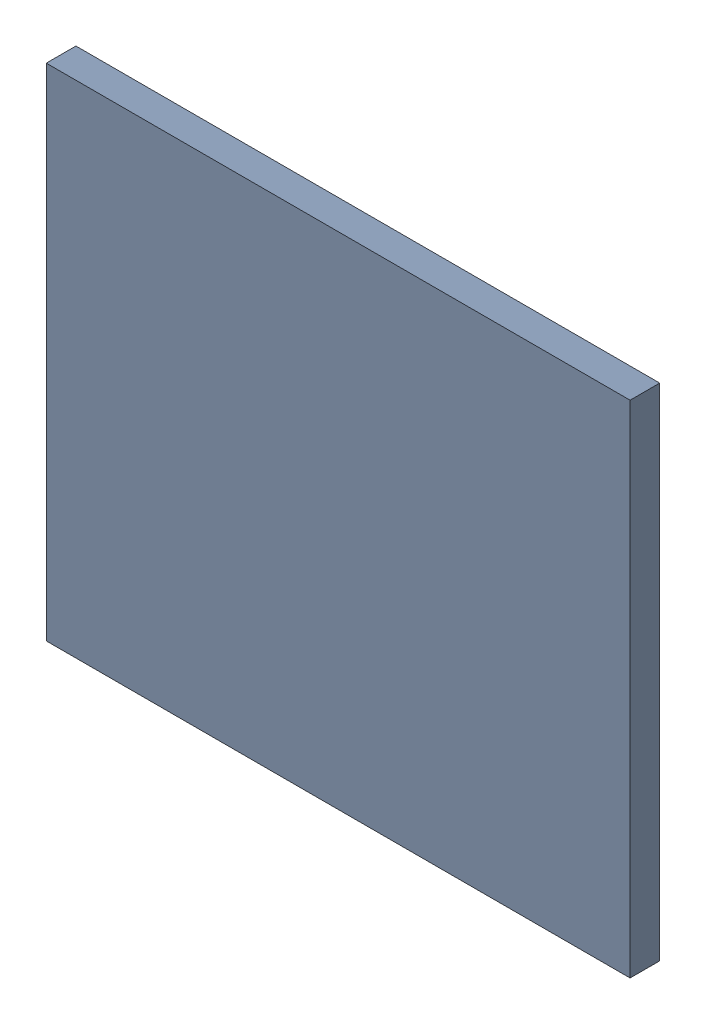
SolidWorks assembly Pad R4-2(26.95mm,41.5mm) on Top Layer, configuration Predeterminado. Lengths in mm.
Overall size (0.7 0.6 0.04).
2 component instances, 1 part files, 0 mates.
Components (placement in the parent):
- Pad R4-2(26.95mm,41.5mm) on Top Layer-1-1: Pad R4-2(26.95mm,41.5mm) on Top Layer-1 [Predeterminado] at (-68.317 -44.187 -0.0457) size (0.7 0.6 0.04)
  - Pad R4-2(26.95mm,41.5mm) on Top Layer-Part-1-1: Pad R4-2(26.95mm,41.5mm) on Top Layer-Part-1 [Predeterminado] at origin size (0.7 0.6 0.04)
